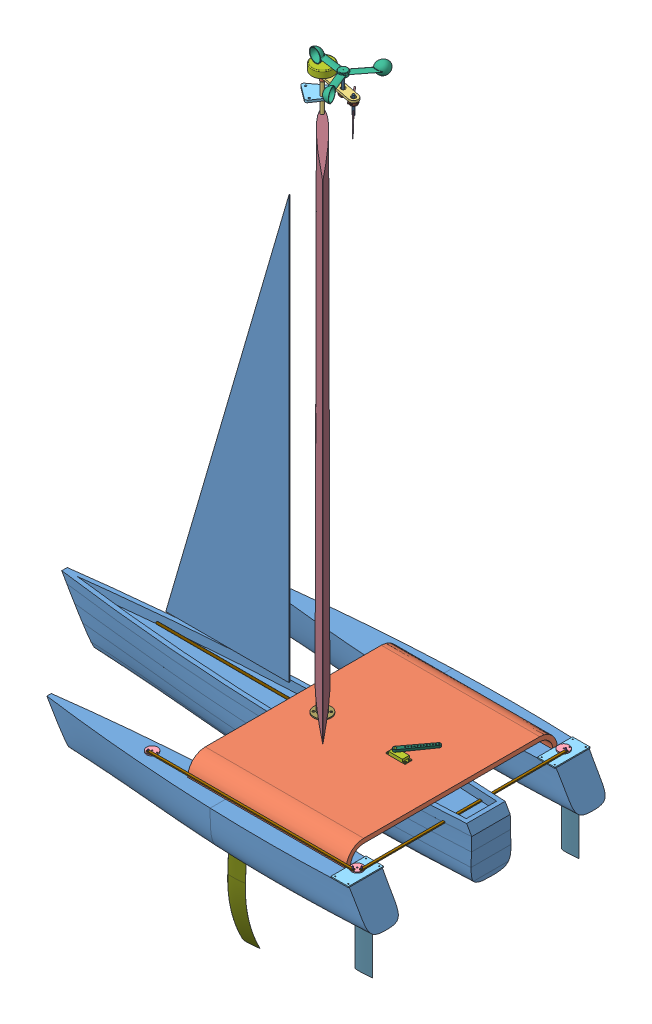
SolidWorks assembly Boat, configuration Default. Lengths in mm.
Overall size (1234.36 2091.54 713.84).
40 component instances, 25 part files, 90 mates.
Components (placement in the parent):
- hull3-1: hull3 [Side Hulls] at (57.4139 -21.1719 -30.5359) size (980.4 121.93 116.94)
- hull3-2: hull3 [Side Hulls] at (57.4139 -21.1719 -627.4359) size (980.4 121.93 116.94)
- deckmold-1: deckmold [Default] at (-52.0449 131.2281 -328.9859) x (0 0 -1) z (1 0 0) size (609.6 50.8 457.2)
- mast-1: mast [Default] at (32.0139 131.2281 -328.9859) size (9.53 1600.2 9.53)
- Rudder wheel-1: Rudder wheel [Default] at (430.5551 93.1281 -30.9678) x (0.99999 0 0.004407) z (0.004407 0 -0.99999) size (31.75 9.53 31.75)
- Rudder wheel-2: Rudder wheel [Default] at (430.5551 93.1281 -627.0039) x (0.436495 0 -0.899707) z (-0.899707 0 -0.436495) size (31.75 9.53 31.75)
- rudder plate-3: rudder plate [Default] at (405.1551 83.6031 -576.2039) x (-1 0 0) z (0 0 1) size (50.8 3.17 101.6)
- rudder plate-4: rudder plate [Default] at (405.1551 83.6031 19.8322) x (-1 0 0) z (0 0 1) size (50.8 3.17 101.6)
- bearing-1: bearing [Default] at (430.5551 80.4281 -627.0039) x (1 0 0.000116) z (-0.000116 0 1) size (6.35 3.17 6.35)
- bearing-2: bearing [Default] at (430.5551 80.4281 -30.9678) x (1 0 -0.000038) z (0.000038 0 1) size (6.35 3.17 6.35)
- servo-1: servo [Default] at (-171.1959 44.4871 -40.7101) x (1 0 0) z (0 -1 0) size (54.97 19.69 43.97)
- Rudder wheel-3: Rudder wheel [Default] at (-161.4804 89.9531 -30.8676) x (0.993645 0 -0.112561) z (-0.112561 0 -0.993645) size (31.75 9.53 31.75)
- pin-1: pin [Default] at (430.4991 102.6531 -18.2679) x (0.444736 0 -0.895662) z (-0.895662 0 -0.444736) size (3.17 12.7 3.17)
- pin-2: pin [Default] at (-160.0509 99.4781 -18.2483) x (0.951912 0 0.306371) z (0.306371 0 -0.951912) size (3.17 12.7 3.17)
- pin-3: pin [Default] at (441.9813 102.6531 -621.4605) x (-0.971218 0 0.238194) z (0.238194 0 0.971218) size (3.17 12.7 3.17)
- pin-4: pin [Default] at (443.2549 89.9531 -30.9118) x (0.988028 0 0.154278) z (-0.154278 0 0.988028) size (3.17 12.7 3.17)
- transfer arm-1: transfer arm [Default] at (440.0868 93.1281 -27.73) x (-0.002157 0 -0.999998) z (0.999998 0 -0.002157) size (596.9 3.17 6.35)
- encoder shaft-1: encoder shaft [Default] at (144.149 1744.1281 -306.8452) x (1 0 0) z (0 0 -1) size (6.35 50.8 6.35)
- encoder shaft-3: encoder shaft [Default] at (106.7706 1770.8997 -314.2254) x (-0.72861 0 0.684929) z (0.684929 0 0.72861) size (6.35 50.8 6.35)
- E4P-X-250-X-S-H-D-X-3: E4P-X-250-X-S-H-D-X [Default] at (106.7706 1731.4281 -314.2254) x (0.988935 0 -0.148349) z (-0.148349 0 -0.988935) size (24.23 14.38 21.67)
- mast top-2: mast top [Default] at (32.0139 131.2281 -328.9859) x (-0.042201 0 0.999109) z (-0.999109 0 -0.042201) size (50.8 28.57 50.8)
- Mainsail2-1: Mainsail2 [Default] at (20.752 258.2281 -340.1746) x (0.709407 0 0.704799) z (-0.704799 0 0.709407) size (312.52 1371.7 30.54)
- rudder2-1: rudder2 [Default] at (424.2051 -160.8719 -30.9958) x (0.99999 0 0.004407) z (-0.004407 0 0.99999) size (50.8 254 5.11)
- rudder2-2: rudder2 [Default] at (424.2051 -160.8719 -627.0319) x (0.99999 0 0.004407) z (-0.004407 0 0.99999) size (50.8 254 5.11)
- transfer arm-3: transfer arm [Default] at (433.6742 93.1281 -15.093) x (-1 0 0.000033) z (-0.000033 0 -1) size (596.9 3.17 6.35)
- sail_servo_assembly-1: sail_servo_assembly [Default] at (257.4143 122.6975 -331.4952) x (1 0 0) z (0 -1 0) size (77.98 90.74 43.97)
  - servo-1: servo [Default] at (-24.8522 -7.3967 18.1394) size (54.97 19.69 43.97)
  - servo_arm-1: servo_arm [Default] at (-18.8029 7.5096 -19.478) x (0.586437 -0.809995 0) z (0.809995 0.586437 0) size (101.6 6.35 12.5)
- centerboard-l-1: centerboard-l [Default] at (57.4139 56.9495 -30.5359) x (1 0 0) z (0 -1 0) size (51.41 47.94 352.18)
- centerboard-r-1: centerboard-r [Default] at (57.4139 80.3223 -627.4359) x (1 0 0) z (0 -1 0) size (67.95 47.94 352.18)
- jib_spear-1: jib_spear [Default] at (-39.3449 117.7511 -328.9859) x (0 0 -1) z (0 1 0) size (6.35 406.4 6.35)
- jib-1: jib [Default] at (-51.25 171.6913 -318.3382) size (355.6 1219.2 2.54)
- mast cap 2-1: mast cap 2 [Default] at (32.0139 1712.3781 -328.9859) x (0.193706 0 -0.98106) z (0.98106 0 0.193706) size (25.4 19.05 25.4)
- weather station 2-1: weather station 2 [Default] at (32.0139 1731.4281 -328.9859) x (0.98106 0 0.193706) z (-0.193706 0 0.98106) size (139.7 6.35 25.4)
- vane2-1: vane2 [Default] at (139.773 1706.0281 -311.4467) x (0.724641 0 -0.689127) z (-0.689127 0 -0.724641) size (3.17 25.4 152.4)
- shroud_mast_cap-1: shroud_mast_cap [Default] at (32.0139 1667.9281 -328.9859) x (0 0 -1) z (1 0 0) size (70.68 6.35 70.68)
- aneometer3-1: aneometer3 [Default] at (146.9713 1777.2497 -241.499) x (-0.38027 0 -0.924876) z (0.924876 0 -0.38027) size (160.65 38.1 178.53)
- E4P-X-250-X-S-H-D-X-4: E4P-X-250-X-S-H-D-X [Default] at (144.149 1731.4281 -306.8452) x (-0.444824 0 -0.895618) z (-0.895618 0 0.444824) size (24.23 14.38 21.67)
- Garmin-2: Garmin [Default] at (32.0139 1737.7781 -328.9859) size (60.96 19.56 60.96)
- hull3-3: hull3 [Center Hull] at (-35.2003 -21.2245 -328.9859) size (1230.99 168.56 186.75)
Mates (geometry in assembly coordinates):
- Coincident4: coincident aligned: plane of hull3-1 through (514.6139 80.4281 13.9141) normal (0 1 0); plane of hull3-2 through (514.6139 80.4281 -582.9859) normal (0 1 0)
- Coincident8: coincident aligned: line of hull3-2 through (-458.4449 80.4281 -627.4359) axis (1 0 0); line of deckmold-1 through (-52.0449 80.4281 -627.4359) axis (1 0 0)
- Coincident9: coincident aligned: line of hull3-1 through (-458.4449 80.4281 -30.5359) axis (1 0 0); line of deckmold-1 through (-52.0449 80.4281 -30.5359) axis (1 0 0)
- Coincident10: coincident anti-aligned: line of hull3-1 through (-458.4449 80.4281 -30.5359) axis (0 0 -1); line of hull3-2 through (-458.4449 80.4281 -627.4359) axis (0 0 1)
- Distance1: distance = 50.8 mm: plane of deckmold-1 through (405.1551 80.4281 -582.9859) normal (1 0 0); line of hull3-1 through (455.9551 80.4281 -78.5034) axis (0 0 1)
- Coincident20: coincident anti-aligned: plane of deckmold-1 through (-52.0449 131.2281 -328.9859) normal (0 0 -1); plane of mast-1 through (32.0139 131.2281 -328.9859) normal (0 0 1)
- Parallel5: parallel aligned: plane of deckmold-1; plane of mast-1 through (32.0139 131.2281 -328.9859) normal (0 1 0)
- Coincident22: coincident: line of hull3-1 through (32.0139 80.4281 -80.3255) axis (0 0 1); plane of mast-1 through (32.0139 131.2281 -328.9859) normal (1 0 0)
- Coincident37: coincident anti-aligned: plane of hull3-2 through (514.6139 80.4281 -582.9859) normal (0 1 0); plane of rudder plate-3 through (405.1551 80.4281 -576.2039) normal (0 -1 0)
- Coincident38: coincident aligned: line of hull3-2 through (455.9551 80.4281 -675.4034) axis (0 0 1); line of rudder plate-3 through (455.9551 80.4281 -677.8039) axis (0 0 1)
- Coincident39: coincident: curve of hull3-2; point of rudder plate-3
- Coincident40: coincident anti-aligned: plane of hull3-1 through (514.6139 80.4281 13.9141) normal (0 1 0); plane of rudder plate-4 through (405.1551 80.4281 19.8322) normal (0 -1 0)
- Coincident41: coincident aligned: line of hull3-1 through (455.9551 80.4281 -78.5034) axis (0 0 1); line of rudder plate-4 through (455.9551 80.4281 -81.7678) axis (0 0 1)
- Coincident42: coincident: curve of hull3-1; point of rudder plate-4
- Coincident43: coincident aligned: plane of rudder plate-4 through (405.1551 83.6031 19.8322) normal (0 1 0); plane of bearing-2 through (430.5551 83.6031 -30.9678) normal (0 1 0)
- Concentric6: concentric anti-aligned: cylinder of rudder plate-4 through (430.5551 80.4281 -30.9678) axis (0 1 0) radius 3.175; cylinder of bearing-2 through (430.5551 83.6031 -30.9678) axis (0 -1 0) radius 3.175
- Coincident44: coincident aligned: plane of rudder plate-3 through (405.1551 83.6031 -576.2039) normal (0 1 0); plane of bearing-1 through (430.5551 83.6031 -627.0039) normal (0 1 0)
- Concentric7: concentric anti-aligned: cylinder of rudder plate-3 through (430.5551 80.4281 -627.0039) axis (0 1 0) radius 3.175; cylinder of bearing-1 through (430.5551 83.6031 -627.0039) axis (0 -1 0) radius 3.175
- Coincident45: coincident anti-aligned: plane of Rudder wheel-2 through (430.5551 83.6031 -627.0039) normal (0 -1 0); plane of rudder plate-3 through (405.1551 83.6031 -576.2039) normal (0 1 0)
- Coincident46: coincident anti-aligned: plane of Rudder wheel-1 through (430.5551 83.6031 -30.9678) normal (0 -1 0); plane of rudder plate-4 through (405.1551 83.6031 19.8322) normal (0 1 0)
- Coincident47: coincident aligned: plane of hull3-1 through (514.6139 80.4281 13.9141) normal (0 1 0); plane of servo-1 through (-171.1959 80.4281 -21.0251) normal (0 1 0)
- Parallel6: parallel aligned: line of deckmold-1 through (405.1551 131.2281 -74.9859) axis (-1 0 0); line of servo-1 through (-130.8099 80.4281 -40.7101) axis (-1 0 0)
- Parallel7: parallel anti-aligned: line of deckmold-1 through (405.1551 131.2281 -74.9859) axis (-1 0 0); line of rudder plate-4 through (405.1551 83.6031 -81.7678) axis (1 0 0)
- Parallel8: parallel aligned: line of deckmold-1 through (405.1551 131.2281 -582.9859) axis (-1 0 0); line of rudder plate-3 through (455.9551 83.6031 -576.2039) axis (-1 0 0)
- Concentric10: concentric aligned: cylinder of servo-1 through (-161.4804 88.4545 -30.8676) axis (0 -1 0) radius 2.9845; cylinder of Rudder wheel-3 through (-161.4804 89.9531 -30.8676) axis (0 -1 0) radius 1.5875
- Coincident51: coincident anti-aligned: plane of hull3-1 through (514.6139 80.4281 13.9141) normal (0 1 0); plane of Rudder wheel-3 through (-161.4804 80.4281 -30.8676) normal (0 -1 0)
- Coincident52: coincident aligned: plane of Rudder wheel-1 through (430.5551 89.9531 -30.9678) normal (0 -1 0); plane of pin-1 through (430.4991 89.9531 -18.2679) normal (0 -1 0)
- Concentric12: concentric aligned: cylinder of Rudder wheel-1 through (430.4991 89.9531 -18.2679) axis (0 1 0) radius 1.5875; cylinder of pin-1 through (430.4991 89.9531 -18.2679) axis (0 1 0) radius 1.5875
- Coincident53: coincident aligned: plane of pin-1 through (430.4991 102.6531 -18.2679) normal (0 1 0); plane of pin-4 through (443.2549 102.6531 -30.9118) normal (0 1 0)
- Concentric13: concentric anti-aligned: cylinder of Rudder wheel-1 through (443.2549 89.9531 -30.9118) axis (0 1 0) radius 1.5875; cylinder of pin-4 through (443.2549 102.6531 -30.9118) axis (0 -1 0) radius 1.5875
- Coincident54: coincident aligned: plane of Rudder wheel-2 through (430.5551 89.9531 -627.0039) normal (0 -1 0); plane of pin-3 through (441.9813 89.9531 -621.4605) normal (0 -1 0)
- Concentric14: concentric aligned: cylinder of Rudder wheel-2 through (441.9813 89.9531 -621.4605) axis (0 1 0) radius 1.5875; cylinder of pin-3 through (441.9813 89.9531 -621.4605) axis (0 1 0) radius 1.5875
- Coincident55: coincident aligned: plane of Rudder wheel-3 through (-161.4804 86.7781 -30.8676) normal (0 -1 0); plane of pin-2 through (-160.0509 86.7781 -18.2483) normal (0 -1 0)
- Concentric15: concentric aligned: cylinder of Rudder wheel-3 through (-160.0509 86.7781 -18.2483) axis (0 1 0) radius 1.5875; cylinder of pin-2 through (-160.0509 86.7781 -18.2483) axis (0 1 0) radius 1.5875
- Concentric18: concentric aligned: cylinder of pin-4 through (443.2549 102.6531 -30.9118) axis (0 -1 0) radius 1.5875; cylinder of transfer arm-1 through (443.2549 96.3031 -30.9118) axis (0 -1 0) radius 1.5875
- Concentric19: concentric anti-aligned: cylinder of pin-3 through (441.9813 89.9531 -621.4605) axis (0 1 0) radius 1.5875; cylinder of transfer arm-1 through (441.9813 96.3031 -621.4605) axis (0 -1 0) radius 1.5875
- Coincident57: coincident anti-aligned: plane of Rudder wheel-1 through (430.5551 93.1281 -30.9678) normal (0 1 0); plane of transfer arm-1 through (440.0868 93.1281 -27.73) normal (0 -1 0)
- Coincident63: coincident anti-aligned: plane of deckmold-1 through (405.1551 131.2281 -328.9859) normal (0 1 0); plane of mast-1 through (32.0139 131.2281 -328.9859) normal (0 -1 0)
- Distance4: distance = 61.2819 mm: line of servo-1 through (-130.8099 80.4281 -40.7101) axis (-1 0 0); line of deckmold-1 through (405.1551 131.2281 -74.9859) axis (-1 0 0)
- Distance5: distance = 93.726 mm: line of servo-1 through (-130.8099 80.4281 -21.0251) axis (0 0 -1); line of deckmold-1 through (-52.0449 131.2281 -74.9859) axis (0 0 -1)
- Concentric32: concentric aligned: cylinder of encoder shaft-3 through (106.7706 1720.0997 -314.2254) axis (0 1 0) radius 3.175; cylinder of E4P-X-250-X-S-H-D-X-3 through (106.7706 1728.7103 -314.2254) axis (0 1 0) radius 3.175
- Concentric34: concentric aligned: cylinder of mast-1 through (32.0139 1731.4281 -328.9859) axis (0 -1 0) radius 4.7625; cylinder of mast top-2 through (32.0139 159.8031 -328.9859) axis (0 -1 0) radius 4.7625
- Coincident92: coincident anti-aligned: plane of deckmold-1 through (405.1551 131.2281 -328.9859) normal (0 1 0); plane of mast top-2 through (32.0139 131.2281 -328.9859) normal (0 -1 0)
- Concentric35: concentric anti-aligned: cylinder of mast-1 through (32.0139 1731.4281 -328.9859) axis (0 -1 0) radius 4.7625; cylinder of Mainsail2-1 through (32.0139 258.1781 -328.9859) axis (0 1 0) radius 4.7625
- Distance8: distance = 127 mm anti-aligned: plane of deckmold-1 through (405.1551 131.2281 -328.9859) normal (0 1 0); plane of Mainsail2-1 through (137.2495 258.2281 -243.5053) normal (0 -1 0)
- Concentric36: concentric aligned: cylinder of Rudder wheel-1 through (430.5551 93.1281 -30.9678) axis (0 -1 0) radius 1.5875; cylinder of rudder2-1 through (430.5551 93.1281 -30.9678) axis (0 -1 0) radius 1.5875
- Coincident94: coincident aligned: plane of Rudder wheel-1 through (430.5551 93.1281 -30.9678) normal (0 1 0); plane of rudder2-1 through (430.5551 93.1281 -30.9678) normal (0 1 0)
- Concentric37: concentric aligned: cylinder of Rudder wheel-2 through (430.5551 93.1281 -627.0039) axis (0 -1 0) radius 1.5875; cylinder of rudder2-2 through (430.5551 93.1281 -627.0039) axis (0 -1 0) radius 1.5875
- Coincident95: coincident aligned: plane of Rudder wheel-2 through (430.5551 93.1281 -627.0039) normal (0 1 0); plane of rudder2-2 through (430.5551 93.1281 -627.0039) normal (0 1 0)
- Parallel12: parallel aligned: plane of rudder2-1 through (424.2051 -160.8719 -30.9958) normal (-0.004407 0 0.99999); plane of rudder2-2 through (424.2051 -160.8719 -627.0319) normal (-0.004407 0 0.99999)
- Concentric38: concentric aligned: cylinder of Rudder wheel-2 through (430.5551 83.6031 -627.0039) axis (0 1 0) radius 6.35; circle of bearing-1
- Concentric42: concentric aligned: cylinder of Rudder wheel-1 through (430.5551 83.6031 -30.9678) axis (0 1 0) radius 6.35; circle of bearing-2
- Concentric43: concentric anti-aligned: cylinder of pin-1 through (430.4991 89.9531 -18.2679) axis (0 1 0) radius 1.5875; cylinder of transfer arm-3 through (430.4991 96.3031 -18.2679) axis (0 -1 0) radius 1.5875
- Concentric44: concentric anti-aligned: cylinder of pin-2 through (-160.0509 86.7781 -18.2483) axis (0 1 0) radius 1.5875; cylinder of transfer arm-3 through (-160.0509 96.3031 -18.2483) axis (0 -1 0) radius 1.5875
- Coincident99: coincident anti-aligned: plane of Rudder wheel-1 through (430.5551 93.1281 -30.9678) normal (0 1 0); plane of transfer arm-3 through (433.6742 93.1281 -15.093) normal (0 -1 0)
- Coincident100: coincident anti-aligned: plane of Rudder wheel-1 through (430.5551 93.1281 -30.9678) normal (0.004407 0 -0.99999); plane of rudder2-1 through (424.2051 -160.8719 -30.9958) normal (-0.004407 0 0.99999)
- Coincident101: coincident anti-aligned: plane of deckmold-1 through (232.5621 80.4281 -338.8919) normal (0 0 1); plane of sail_servo_assembly-1/servo-1 through (232.5621 131.2281 -338.8919) normal (0 0 -1)
- Coincident102: coincident anti-aligned: plane of deckmold-1 through (405.1551 131.2281 -328.9859) normal (0 1 0); plane of sail_servo_assembly-1/servo-1 through (232.5621 131.2281 -319.2069) normal (0 -1 0)
- Coincident103: coincident anti-aligned: plane of deckmold-1 through (232.5621 80.4281 -338.8919) normal (1 0 0); plane of sail_servo_assembly-1/servo-1 through (232.5621 104.5581 -319.2069) normal (-1 0 0)
- Coincident112: coincident aligned: plane of hull3-1 through (57.4139 -21.1719 -30.5359) normal (0 0 1); plane of centerboard-l-1 through (57.4139 56.9495 -30.5359) normal (0 0 1)
- Coincident113: coincident aligned: plane of hull3-1 through (57.4139 -21.1719 -30.5359) normal (1 0 0); plane of centerboard-l-1
- Coincident116: coincident aligned: plane of hull3-2 through (57.4139 -21.1719 -627.4359) normal (1 0 0); plane of centerboard-r-1
- Coincident117: coincident aligned: plane of hull3-2 through (57.4139 -21.1719 -627.4359) normal (0 0 1); plane of centerboard-r-1 through (57.4139 80.3223 -627.4359) normal (0 0 1)
- Coincident121: coincident anti-aligned: plane of deckmold-1 through (405.1551 118.5281 -328.9859) normal (0 -1 0); plane of jib_spear-1 through (-52.0449 118.5281 -325.2042) normal (0 1 0)
- Coincident122: coincident anti-aligned: plane of deckmold-1 through (-52.0449 80.4281 -582.9859) normal (-1 0 0); plane of jib_spear-1 through (-52.0449 117.7511 -328.9859) normal (1 0 0)
- Coincident123: coincident aligned: plane of deckmold-1 through (-52.0449 131.2281 -328.9859) normal (0 0 -1); plane of jib_spear-1
- Concentric45: concentric anti-aligned: cylinder of mast-1 through (32.0139 1731.4281 -328.9859) axis (0 -1 0) radius 4.7625; cylinder of mast cap 2-1 through (32.0139 1712.3781 -328.9859) axis (0 1 0) radius 4.7676
- Coincident137: coincident aligned: plane of mast-1 through (32.0139 1731.4281 -328.9859) normal (0 1 0); plane of mast cap 2-1 through (32.0139 1731.4281 -328.9859) normal (0 1 0)
- Concentric48: concentric aligned: cylinder of encoder shaft-3 through (106.7706 1720.0997 -314.2254) axis (0 1 0) radius 3.175; cylinder of weather station 2-1 through (106.7706 1737.7781 -314.2254) axis (0 1 0) radius 3.3735
- Coincident143: coincident anti-aligned: plane of E4P-X-250-X-S-H-D-X-3 through (106.7706 1731.4281 -314.2254) normal (0 1 0); plane of weather station 2-1 through (32.0139 1731.4281 -328.9859) normal (0 -1 0)
- Coincident144: coincident aligned: plane of encoder shaft-3 through (106.7706 1720.0997 -314.2254) normal (0 -1 0); plane of E4P-X-250-X-S-H-D-X-3 through (106.7706 1720.0997 -314.2254) normal (0 -1 0)
- Concentric55: concentric aligned: cylinder of encoder shaft-1 through (144.149 1693.3281 -306.8452) axis (0 1 0) radius 3.175; cylinder of vane2-1 through (144.149 1693.3281 -306.8452) axis (0 1 0) radius 3.175
- Coincident147: coincident anti-aligned: plane of encoder shaft-1 through (144.149 1693.3281 -306.8452) normal (0 -1 0); plane of vane2-1 through (144.149 1693.3281 -306.8452) normal (0 1 0)
- Concentric57: concentric aligned: cylinder of mast-1 through (32.0139 1731.4281 -328.9859) axis (0 -1 0) radius 4.7625; cylinder of shroud_mast_cap-1 through (32.0139 1674.2781 -328.9859) axis (0 -1 0) radius 3.175
- Parallel21: parallel aligned: line of deckmold-1 through (-52.0449 131.2281 -74.9859) axis (0 0 -1); line of shroud_mast_cap-1 through (19.3139 1674.2781 -303.5859) axis (0 0 -1)
- Distance11: distance = 38.1 mm anti-aligned: plane of shroud_mast_cap-1 through (32.0139 1674.2781 -328.9859) normal (0 1 0); plane of mast cap 2-1 through (32.0139 1712.3781 -328.9859) normal (0 -1 0)
- Coincident149: coincident anti-aligned: plane of mast cap 2-1 through (32.0139 1731.4281 -328.9859) normal (0 1 0); plane of weather station 2-1 through (32.0139 1731.4281 -328.9859) normal (0 -1 0)
- Concentric60: concentric aligned: cylinder of mast cap 2-1 through (22.5447 1731.4281 -330.8555) axis (0 1 0) radius 2.1526; cylinder of weather station 2-1 through (22.5447 1737.7781 -330.8555) axis (0 1 0) radius 2.1526
- Concentric61: concentric aligned: cylinder of mast cap 2-1 through (35.1293 1731.4281 -319.8505) axis (0 1 0) radius 2.1526; cylinder of weather station 2-1 through (35.1293 1737.7781 -319.8505) axis (0 1 0) radius 2.1526
- Coincident150: coincident anti-aligned: plane of encoder shaft-3 through (106.7706 1770.8997 -314.2254) normal (0 1 0); circle of aneometer3-1
- Concentric62: concentric anti-aligned: cylinder of encoder shaft-3 through (106.7706 1720.0997 -314.2254) axis (0 1 0) radius 3.175; cylinder of aneometer3-1 through (106.7706 1796.2997 -314.2254) axis (0 -1 0) radius 0.7937
- Coincident151: coincident anti-aligned: plane of weather station 2-1 through (32.0139 1731.4281 -328.9859) normal (0 -1 0); plane of E4P-X-250-X-S-H-D-X-4 through (144.149 1731.4281 -306.8452) normal (0 1 0)
- Concentric63: concentric anti-aligned: cylinder of weather station 2-1 through (144.149 1734.6031 -306.8452) axis (0 1 0) radius 6.35; cone of E4P-X-250-X-S-H-D-X-4 through (144.149 1728.6341 -306.8452) axis (0 -1 0)
- Concentric64: concentric aligned: cylinder of encoder shaft-1 through (144.149 1693.3281 -306.8452) axis (0 1 0) radius 3.175; cylinder of weather station 2-1 through (144.149 1734.6031 -306.8452) axis (0 1 0) radius 6.35
- Distance12: distance = 6.35 mm aligned: plane of encoder shaft-1 through (144.149 1744.1281 -306.8452) normal (0 1 0); plane of weather station 2-1 through (32.0139 1737.7781 -328.9859) normal (0 1 0)
- Coincident153: coincident anti-aligned: plane of weather station 2-1 through (32.0139 1737.7781 -328.9859) normal (0 1 0); plane of Garmin-2 through (32.0139 1737.7781 -328.9859) normal (0 -1 0)
- Concentric65: concentric aligned: circle of weather station 2-1; circle of Garmin-2
- Coincident154: coincident anti-aligned: plane of deckmold-1 through (405.1551 118.5281 -328.9859) normal (0 -1 0); plane of hull3-3 through (-33.7638 118.5281 -328.9859) normal (0 1 0)
- Coincident157: coincident anti-aligned: plane of deckmold-1 through (-52.0449 131.2281 -328.9859) normal (0 0 -1); plane of hull3-3 through (-33.7638 -21.2245 -328.9859) normal (0 0 1)
- Coincident158: coincident aligned: plane of hull3-2 through (514.6139 -21.1719 -685.9064) normal (0.866025 0.5 0); plane of hull3-3 through (521.9462 -33.8719 -402.074) normal (0.866025 0.5 0)
